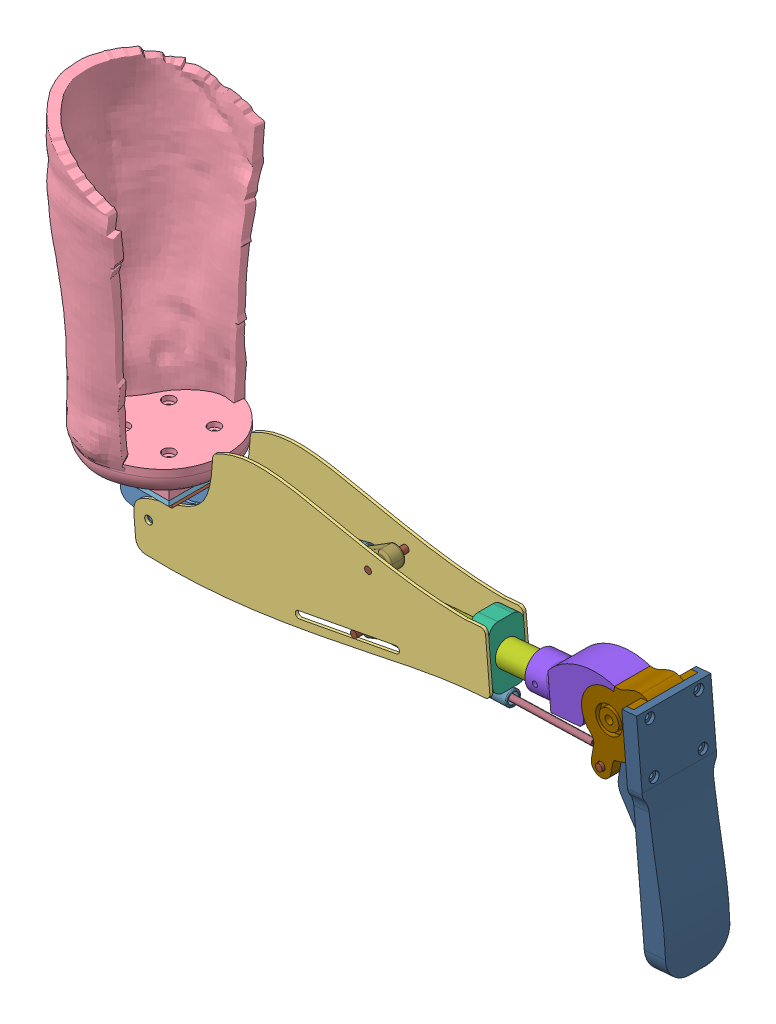
SolidWorks assembly Assem1, configuration Default. Lengths in mm.
Overall size (635.26 485.98 155.79).
24 component instances, 14 part files, 58 mates.
Components (placement in the parent):
- component1-1: component1 [Default] at (5.4956 60.0364 72.0654) x (1 0 0) z (0 -1 0) size (91.53 3 46.56)
- component1.2-1: component1.2 [Default] at (2.9956 75.0364 88.5654) x (0 0 -1) z (1 0 0) size (59 3 65)
- component1-2: component1 [Default] at (5.4956 60.0364 102.0654) x (1 0 0) z (0 -1 0) size (91.53 3 46.56)
- component2-1: component2 [Default] at (2.9956 44.0364 106.0654) x (-0.086107 0.996286 0) z (0.996286 0.086107 0) size (140.92 3 360)
- socket-1: socket [Default] at (-6.974 237.8303 85.458) x (-1 0 0) z (0 0 -1) size (156.26 311.75 155.79)
- component4-1: component4 [Default] at (2.9956 78.0364 88.5654) size (65 5 65)
- component2-2: component2 [Default] at (2.9956 44.0364 68.0654) x (-0.086107 0.996286 0) z (0.996286 0.086107 0) size (140.92 3 360)
- component3-1: component3 [Default] at (345.4227 88.6876 88.5654) x (0 0 -1) z (-0.086107 0.996286 0) size (35 20 60)
- 150mmPVC-1: 150mmPVC [Default] at (425.1255 95.5762 88.5654) x (-0.086107 0.996286 0) z (0 0 1) size (25.4 150 25.4)
- component-2-1: component-2 [Default] at (465.3755 99.0549 88.5654) x (0.086107 -0.996286 0) z (0 0 1) size (64.13 113.1 36)
- component-5-1: component-5 [Default] at (500.644 102.1031 88.5654) x (0 0 -1) z (0.086107 -0.996286 0) size (65 70.1 90.64)
- component-6-1: component-6 [Default] at (500.644 102.1031 88.5654) x (0.086107 -0.996286 0) z (0 0 -1) size (230 56.58 75)
- shaft-1: shaft [Default] at (210.12 47.528 68.0654) x (0.993473 -0.114067 0) z (-0.114067 -0.993473 0) size (6.9 41 6.9)
- shaft-2: shaft [Default] at (50.4956 65.0364 68.0654) x (0.993473 -0.114067 0) z (-0.114067 -0.993473 0) size (6.9 41 6.9)
- shaft-3: shaft [Default] at (224.5643 110.8632 68.0654) x (0.993473 -0.114067 0) z (-0.114067 -0.993473 0) size (6.9 41 6.9)
- shockmount-1: shockmount [Default] at (50.4956 65.0364 88.5654) x (0.254593 -0.967048 0) z (0 0 1) size (20.28 30.01 17.96)
- shockmount-2: shockmount [Default] at (224.5643 110.8632 88.5654) x (-0.254593 0.967048 0) z (0 0 1) size (20.28 30.01 17.96)
- shockmount-3: shockmount [Default] at (210.12 47.528 88.5654) x (0.029167 -0.999575 0) z (0 0 1) size (20.28 30.01 17.96)
- shockmount-4: shockmount [Default] at (457.5147 54.7468 88.5654) x (-0.029167 0.999575 0) z (0 0 1) size (20.28 30.01 17.96)
- shaft-4: shaft [Default] at (457.5147 54.7468 68.0654) x (0.993473 -0.114067 0) z (-0.114067 -0.993473 0) size (6.9 41 6.9)
- pistonrod-1: pistonrod [Varsayılan] at (65.0014 68.8553 88.5654) x (0.228668 -0.868573 -0.439649) z (0.967048 0.254593 0) size (6.17 6 116.38)
- cylinder-1: cylinder [Varsayılan] at (205.2234 105.7714 88.5654) x (-0.967048 -0.254593 0) z (-0.254577 0.966987 -0.011255) size (129.36 15 15)
- pistonrod-2: pistonrod [Varsayılan] at (442.5211 54.3093 88.5654) x (0.026197 -0.897788 0.439649) z (-0.999575 -0.029167 0) size (6.17 6 116.38)
- cylinder-2: cylinder [Varsayılan] at (230.1115 48.1113 88.5654) x (0.999575 0.029167 0) z (-0.019317 0.66202 0.749237) size (129.36 15 15)
Mates (geometry in assembly coordinates):
- Coincident1: coincident anti-aligned: plane of component1-1 through (5.4956 60.0364 72.0654) normal (0 0 -1); plane of component1.2-1 through (2.9956 78.0364 72.0654) normal (0 0 1)
- Coincident2: coincident aligned: plane of component1-1 through (5.4956 78.0364 75.0654) normal (0 1 0); plane of component1.2-1 through (2.9956 78.0364 88.5654) normal (0 1 0)
- Coincident3: coincident anti-aligned: plane of component1-1 through (-9.5044 60.0364 75.0654) normal (-1 0 0); plane of component1.2-1 through (-9.5044 78.0364 88.5654) normal (1 0 0)
- Coincident4: coincident anti-aligned: plane of component1.2-1 through (2.9956 78.0364 102.0654) normal (0 0 1); plane of component1-2 through (5.4956 60.0364 102.0654) normal (0 0 -1)
- Coincident5: coincident aligned: plane of component1.2-1 through (2.9956 78.0364 88.5654) normal (0 1 0); plane of component1-2 through (5.4956 78.0364 105.0654) normal (0 1 0)
- Coincident6: coincident anti-aligned: plane of component1.2-1 through (15.4956 78.0364 88.5654) normal (-1 0 0); plane of component1-2 through (15.4956 60.0364 105.0654) normal (1 0 0)
- Coincident7: coincident aligned: circle of component1.2-1; circle of component4-1
- Coincident9: coincident aligned: circle of component1.2-1; circle of component4-1
- Coincident10: coincident anti-aligned: circle of socket-1; circle of component4-1
- Coincident11: coincident anti-aligned: circle of socket-1; circle of component4-1
- Concentric8: concentric aligned: cylinder of component1-2 through (50.4956 65.0364 105.0654) axis (0 0 -1) radius 3; cylinder of shaft-2 through (50.4956 65.0364 109.0654) axis (0 0 -1) radius 3.45
- Width5: width aligned: plane of component1-2 through (5.4956 60.0364 105.0654) normal (0 0 1); plane of component1-1 through (5.4956 60.0364 72.0654) normal (0 0 -1); plane of shaft-2 through (50.4956 65.0364 109.0654) normal (0 0 1); plane of shaft-2 through (50.4956 65.0364 68.0654) normal (0 0 -1)
- Concentric11: concentric aligned: circle of component1-2; circle of component2-1
- Concentric10: concentric aligned: cylinder of component1-1 through (2.9956 44.0364 75.0654) axis (0 0 -1) radius 4; cylinder of component2-2 through (2.9956 44.0364 71.0654) axis (0 0 -1) radius 4
- Distance2: distance = 1 mm anti-aligned: plane of component2-1 through (2.9956 44.0364 106.0654) normal (0 0 -1); plane of component1-2 through (5.4956 60.0364 105.0654) normal (0 0 1)
- Distance3: distance = 1 mm anti-aligned: plane of component1-1 through (5.4956 60.0364 72.0654) normal (0 0 -1); plane of component2-2 through (2.9956 44.0364 71.0654) normal (0 0 1)
- Coincident16: coincident aligned: plane of component2-1; plane of component3-1
- Coincident17: coincident aligned: plane of component2-1; plane of component3-1
- Width6: width anti-aligned: plane of component2-1 through (2.9956 44.0364 109.0654) normal (0 0 1); plane of component2-2 through (2.9956 44.0364 68.0654) normal (0 0 -1); plane of component3-1 through (322.9137 116.854 71.0654) normal (0 0 -1); plane of component3-1 through (322.9137 116.854 106.0654) normal (0 0 1)
- Concentric12: concentric aligned: cylinder of component3-1 through (325.497 86.9655 88.5654) axis (0.996286 0.086107 0) radius 12.7; cylinder of 150mmPVC-1 through (275.6827 82.6601 88.5654) axis (0.996286 0.086107 0) radius 12.7
- Distance4: distance = 50 mm aligned: plane of 150mmPVC-1 through (275.6827 82.6601 88.5654) normal (-0.996286 -0.086107 0); plane of component3-1 through (325.497 86.9655 88.5654) normal (-0.996286 -0.086107 0)
- Concentric13: concentric anti-aligned: cylinder of 150mmPVC-1 through (275.6827 82.6601 88.5654) axis (0.996286 0.086107 0) radius 12.7; cylinder of component-2-1 through (425.1255 95.5762 88.5654) axis (-0.996286 -0.086107 0) radius 12.7
- Coincident19: coincident anti-aligned: plane of 150mmPVC-1 through (425.1255 95.5762 88.5654) normal (0.996286 0.086107 0); plane of component-2-1 through (425.1255 95.5762 88.5654) normal (-0.996286 -0.086107 0)
- Parallel1: parallel aligned: plane of component3-1 through (322.9137 116.854 106.0654) normal (0 0 1); plane of component-2-1 through (451.9914 71.5382 106.5654) normal (0 0 1)
- Concentric14: concentric anti-aligned: cylinder of component-2-1 through (465.3755 99.0549 81.0654) axis (0 0 1) radius 4; cylinder of component-5-1 through (465.3755 99.0549 106.5654) axis (0 0 -1) radius 4
- Coincident21: coincident anti-aligned: plane of component-2-1 through (465.3755 99.0549 81.0654) normal (0 0 -1); plane of component-5-1 through (500.644 102.1031 81.0654) normal (0 0 1)
- Coincident22: coincident aligned: circle of component-5-1; circle of component-6-1
- Coincident23: coincident aligned: circle of component-5-1; circle of component-6-1
- Slot2: slot aligned: cylinder of component2-1 through (210.12 47.528 109.0654) axis (0 0 -1) radius 3.45; cylinder of shaft-1 through (252.9282 55.6003 109.0654) axis (0 0 -1) radius 3.5
- Width7: width anti-aligned: plane of component2-1 through (2.9956 44.0364 109.0654) normal (0 0 1); plane of component2-2 through (2.9956 44.0364 68.0654) normal (0 0 -1); plane of shaft-1 through (210.12 47.528 68.0654) normal (0 0 -1); plane of shaft-1 through (210.12 47.528 109.0654) normal (0 0 1)
- Width8: width anti-aligned: plane of component2-1 through (2.9956 44.0364 109.0654) normal (0 0 1); plane of component2-2 through (2.9956 44.0364 68.0654) normal (0 0 -1); plane of shaft-3 through (224.5643 110.8632 68.0654) normal (0 0 -1); plane of shaft-3 through (224.5643 110.8632 109.0654) normal (0 0 1)
- Width9: width anti-aligned: plane of component1-2 through (5.4956 60.0364 105.0654) normal (0 0 1); plane of component1-1 through (5.4956 60.0364 72.0654) normal (0 0 -1); plane of shaft-2 through (50.4956 65.0364 68.0654) normal (0 0 -1); plane of shaft-2 through (50.4956 65.0364 109.0654) normal (0 0 1)
- Concentric15: concentric aligned: cylinder of component1-2 through (50.4956 65.0364 105.0654) axis (0 0 -1) radius 3; cylinder of shaft-2 through (50.4956 65.0364 109.0654) axis (0 0 -1) radius 3.45
- Concentric16: concentric aligned: cylinder of shaft-3 through (224.5643 110.8632 109.0654) axis (0 0 -1) radius 3.45; cylinder of component2-1 through (224.5643 110.8632 109.0654) axis (0 0 -1) radius 3.45
- Coincident24: coincident anti-aligned: plane of component-2-1 through (471.0877 131.2521 70.5654) normal (0.984624 -0.174685 0); plane of component-5-1 through (471.093 131.2819 20.2772) normal (-0.984624 0.174685 0)
- Parallel2: parallel anti-aligned: plane of component1.2-1 through (2.9956 75.0364 88.5654) normal (0 -1 0); plane of component2-1
- Coincident26: coincident aligned: plane of component2-1; plane of component2-2
- Concentric17: concentric aligned: cylinder of component-5-1 through (457.5147 54.7468 121.0654) axis (0 0 -1) radius 4; cylinder of shockmount-4 through (457.5147 54.7468 96.5654) axis (0 0 -1) radius 4
- Width10: width aligned: plane of component-5-1 through (500.644 102.1031 106.5654) normal (0 0 1); plane of shockmount-4 through (500.644 102.1031 70.5654) normal (0 0 -1); plane of component-5-1 through (467.2188 65.0342 96.5654) normal (0 0 1); plane of shockmount-4 through (467.8021 45.0427 80.5654) normal (0 0 -1)
- Width11: width aligned: plane of component1-2 through (5.4956 60.0364 105.0654) normal (0 0 1); plane of shockmount-1 through (5.4956 60.0364 72.0654) normal (0 0 -1); plane of component1-1 through (43.3711 52.82 96.5654) normal (0 0 1); plane of shockmount-1 through (38.2792 72.161 80.5654) normal (0 0 -1)
- Concentric18: concentric aligned: cylinder of shaft-2 through (50.4956 65.0364 109.0654) axis (0 0 -1) radius 3.45; cylinder of shockmount-1 through (50.4956 65.0364 96.5654) axis (0 0 -1) radius 4
- Concentric19: concentric aligned: cylinder of shaft-3 through (224.5643 110.8632 109.0654) axis (0 0 -1) radius 3.45; cylinder of shockmount-2 through (224.5643 110.8632 96.5654) axis (0 0 -1) radius 4
- Concentric20: concentric aligned: cylinder of shaft-1 through (210.12 47.528 109.0654) axis (0 0 -1) radius 3.45; cylinder of shockmount-3 through (210.12 47.528 96.5654) axis (0 0 -1) radius 4
- Width12: width anti-aligned: plane of component2-1 through (2.9956 44.0364 109.0654) normal (0 0 1); plane of shockmount-3 through (2.9956 44.0364 68.0654) normal (0 0 -1); plane of component2-2 through (199.8326 57.232 80.5654) normal (0 0 -1); plane of shockmount-3 through (200.4159 37.2405 96.5654) normal (0 0 1)
- Concentric21: concentric aligned: cylinder of component-5-1 through (457.5147 54.7468 121.0654) axis (0 0 -1) radius 4; cylinder of shaft-4 through (457.5147 54.7468 109.0654) axis (0 0 -1) radius 3.45
- Width14: width anti-aligned: plane of component-5-1 through (500.644 102.1031 106.5654) normal (0 0 1); plane of shaft-4 through (500.644 102.1031 70.5654) normal (0 0 -1); plane of component-5-1 through (457.5147 54.7468 68.0654) normal (0 0 -1); plane of shaft-4 through (457.5147 54.7468 109.0654) normal (0 0 1)
- Concentric22: concentric anti-aligned: cylinder of shockmount-1 through (60.1661 67.5823 88.5654) axis (0.967048 0.254593 0) radius 2.5; cylinder of pistonrod-1 through (177.179 98.3881 88.5654) axis (-0.967048 -0.254593 0) radius 3
- Distance5: distance = 5 mm anti-aligned: plane of shockmount-1 through (60.1661 67.5823 88.5654) normal (0.967048 0.254593 0); plane of pistonrod-1 through (65.0014 68.8553 88.5654) normal (-0.967048 -0.254593 0)
- Concentric30: concentric anti-aligned: circle of shockmount-2; cylinder of cylinder-1 through (205.2234 105.7714 88.5654) axis (0.967048 0.254593 0) radius 7.5
- Coincident33: coincident anti-aligned: plane of shockmount-2 through (205.2234 105.7714 88.5654) normal (-0.967048 -0.254593 0); plane of cylinder-1 through (205.2148 105.804 91.5652) normal (0.967048 0.254593 0)
- Concentric31: concentric anti-aligned: cylinder of pistonrod-1 through (177.179 98.3881 88.5654) axis (-0.967048 -0.254593 0) radius 3; cylinder of cylinder-1 through (205.2234 105.7714 88.5654) axis (0.967048 0.254593 0) radius 6
- LimitDistance2: limit distance = 28 mm anti-aligned: plane of pistonrod-1 through (177.179 98.3881 88.5654) normal (0.967048 0.254593 0); plane of cylinder-1 through (204.242 105.5712 93.5651) normal (-0.967048 -0.254593 0)
- Concentric32: concentric anti-aligned: cylinder of shockmount-4 through (447.5189 54.4551 88.5654) axis (-0.999575 -0.029167 0) radius 2.5; cylinder of pistonrod-2 through (326.5704 50.9259 88.5654) axis (0.999575 0.029167 0) radius 3
- Distance10: distance = 5 mm anti-aligned: plane of shockmount-4 through (447.5189 54.4551 88.5654) normal (-0.999575 -0.029167 0); plane of pistonrod-2 through (442.5211 54.3093 88.5654) normal (0.999575 0.029167 0)
- Concentric33: concentric anti-aligned: circle of shockmount-3; cylinder of cylinder-2 through (230.1115 48.1113 88.5654) axis (-0.999575 -0.029167 0) radius 7.5
- Coincident37: coincident anti-aligned: plane of shockmount-3 through (230.1115 48.1113 88.5654) normal (0.999575 0.029167 0); plane of cylinder-2 through (230.0459 50.3581 86.5785) normal (-0.999575 -0.029167 0)
- Concentric35: concentric anti-aligned: cylinder of pistonrod-2 through (326.5704 50.9259 88.5654) axis (0.999575 0.029167 0) radius 3; cylinder of cylinder-2 through (230.1115 48.1113 88.5654) axis (-0.999575 -0.029167 0) radius 6
- LimitDistance3: limit distance = 95.5 mm anti-aligned: plane of pistonrod-2 through (326.5704 50.9259 88.5654) normal (-0.999575 -0.029167 0); plane of cylinder-2 through (231.0018 51.8851 85.2539) normal (0.999575 0.029167 0)
